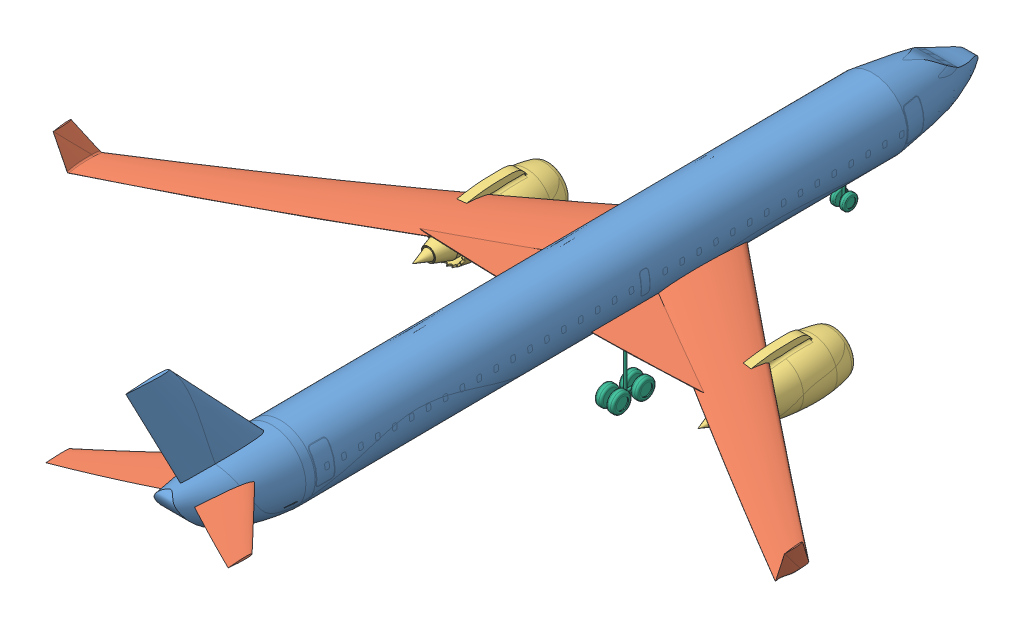
SolidWorks assembly assembledPlane, configuration Default. Lengths in mm.
Overall size (41929.39 13669.44 51278.86).
6 component instances, 6 part files, 13 mates.
Components (placement in the parent):
- fuselage-1: fuselage [Default] at (15305.2926 24893.997 40604.2591) size (40759.68 13669.44 51278.86)
- wing3D-1: wing3D [Default] at (15305.2926 24893.997 40604.2591) x (-1 0 0) z (0 -1 0) size (41929.39 34813.51 3363.45)
- turbofanEngine-1: turbofanEngine [Default] at (15305.2926 24893.997 40604.2591) x (1 0 0) z (0 0 -1) size (40759.68 3692.37 34596.59)
- cargoHold-1: cargoHold [Default] at (15305.2926 24893.997 40604.2591) x (-1 0 0) z (0 0 -1) size (40759.68 1859.28 38041.34)
- passengerCompartment-2: passengerCompartment [Default] at (15305.2926 24800.3894 40603.852) x (1 0 0) z (0 -0.008699 0.999962) size (3901.44 2682.24 39107.13)
- landingGear-1: landingGear [Default] at (15305.2926 24893.997 40604.2591) size (40759.68 5024.59 40807.91)
Mates (geometry in assembly coordinates):
- Coincident3: coincident aligned: line of fuselage-1 through (35685.135 24893.997 46373.8586) axis (0 0 1); line of wing3D-1 through (35685.135 24893.997 46373.8586) axis (0 0 1)
- Coincident4: coincident aligned: line of fuselage-1 through (-5074.5498 24893.997 46373.8586) axis (0 0 1); line of wing3D-1 through (-5074.5498 24893.997 46373.8586) axis (0 0 1)
- Coincident8: coincident: point of fuselage-1; point of wing3D-1
- Coincident10: coincident aligned: line of fuselage-1 through (15296.5527 24893.997 48295.1848) axis (1 0 0); line of turbofanEngine-1 through (15296.5527 24893.997 48295.1848) axis (1 0 0)
- Coincident12: coincident: point of fuselage-1; point of turbofanEngine-1
- Coincident14: coincident: unknown of ?; line of turbofanEngine-1 through (15305.2926 24893.997 29843.8112) axis (0.776647 0 0.629936)
- Coincident15: coincident aligned: line of fuselage-1 through (15314.0326 24893.997 48295.1848) axis (-1 0 0); line of cargoHold-1 through (15314.0326 24893.997 48295.1848) axis (-1 0 0)
- Coincident16: coincident: point of wing3D-1; point of cargoHold-1
- Coincident24: coincident: point of wing3D-1; point of passengerCompartment-2
- Parallel2: parallel aligned: line of cargoHold-1 through (16499.0926 24208.197 50637.2591) axis (-1 0 0); line of passengerCompartment-2 through (17113.6585 24173.9141 54804.1434) axis (-1 0 0)
- Coincident31: coincident: cylinder of fuselage-1 through (15305.9606 25222.785 16445.3208) axis (0.000017 0.008241 -0.999966) radius 1981.2; moEndPointRef_w of passengerCompartment-2
- Coincident32: coincident aligned: line of fuselage-1 through (35685.135 24893.997 46373.8586) axis (0 0 1); line of landingGear-1 through (35685.135 24893.997 46373.8586) axis (0 0 1)
- Coincident33: coincident: point of fuselage-1; point of landingGear-1
